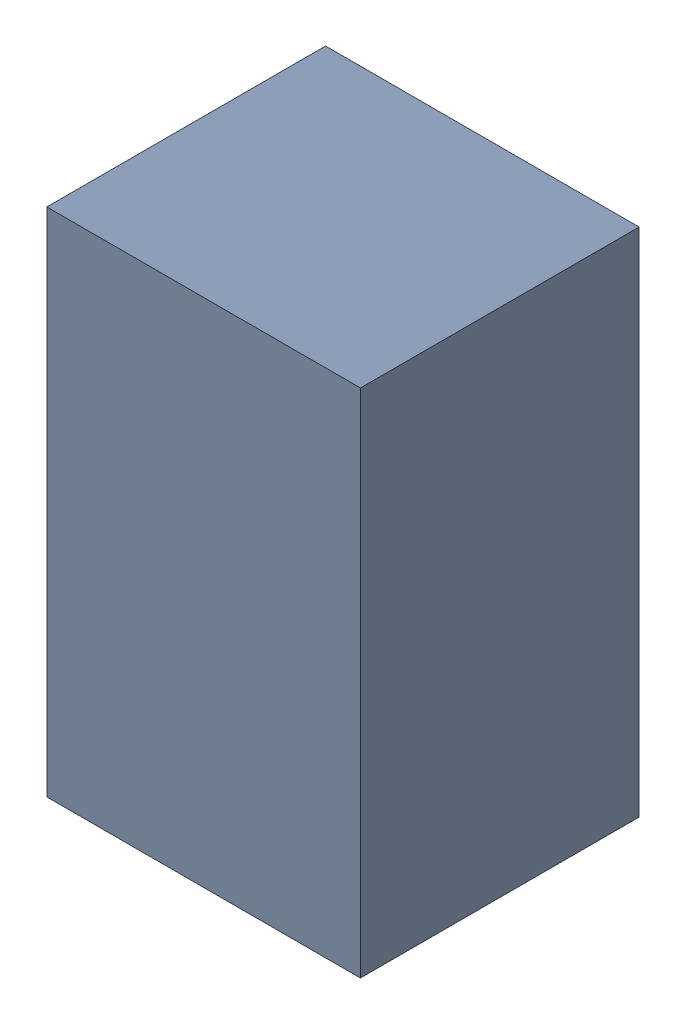
SolidWorks assembly C6_1, configuration Default. Lengths in mm.
Overall size (1.35 2.2 1.2).
2 component instances, 1 part files, 0 mates.
Components (placement in the parent):
- 407985568_1-1: 407985568_1 [Default] at (24.003 12.573 0.0127) size (1.35 2.2 1.2)
  - Extruded_8-1: Extruded_8 [Default] at origin size (1.35 2.2 1.2)
